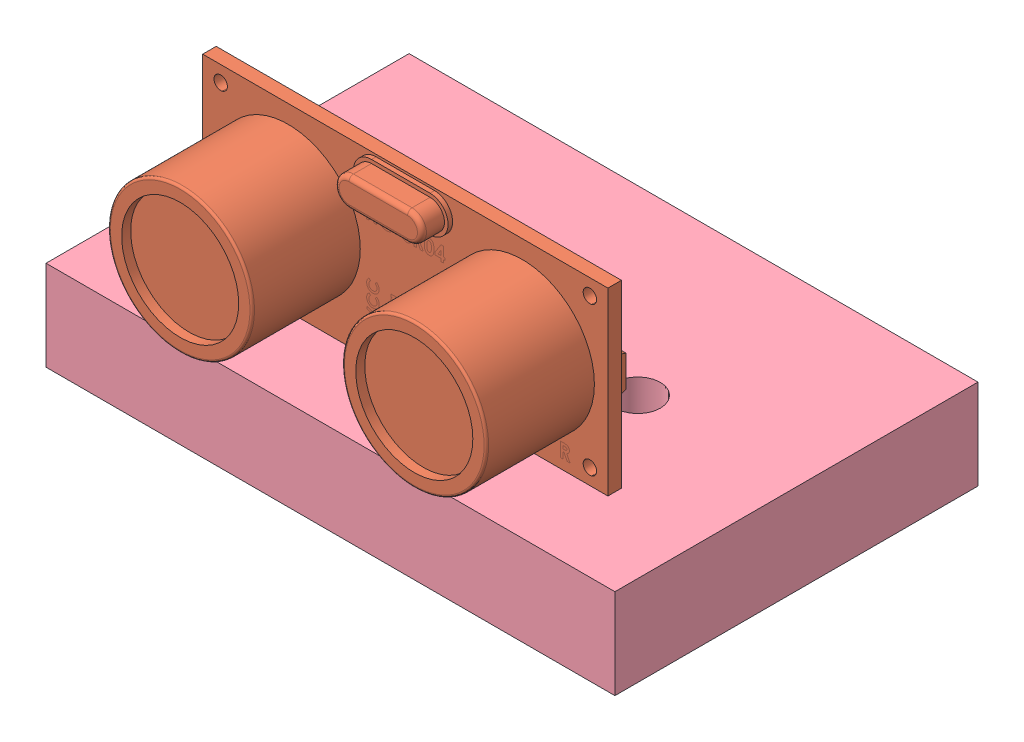
SolidWorks assembly Ultrasonic Jig, configuration Default. Lengths in mm.
Overall size (63.18 35.3 44.01).
8 component instances, 4 part files, 7 mates.
Components (placement in the parent):
- 01.01.03.00_Ultrasonic_with_mount-1: 01.01.03.00_Ultrasonic_with_mount [Default] at origin size (45 35.3 34.01)
  - 01.01.03.01_Ultrasonic_Vero-1: 01.01.03.01_Ultrasonic_Vero [Default] at origin size (43.18 10.5 20.32)
  - Ultrasonic-HCSR04-1: Ultrasonic-HCSR04 [Default] at (21.59 20.5 0.19) size (45 26.6 18)
  - hexagon nut style 1 (grades a and b) as-2: hexagon nut style 1 (grades a and b) as [AS 1112.1 S1 - M3-D-N] at (35.56 0 -10.16) x (0.865385 0 0.501108) z (0 1 0) size (5.5 6.35 2.4)
  - hexagon nut style 1 (grades a and b) as-3: hexagon nut style 1 (grades a and b) as [AS 1112.1 S1 - M3-D-N] at (35.56 -2.4 -10.16) x (0.865385 0 0.501108) z (0 1 0) size (5.5 6.35 2.4)
  - hexagon nut style 1 (grades a and b) as-6: hexagon nut style 1 (grades a and b) as [AS 1112.1 S1 - M3-D-N] at (7.62 0 -10.16) x (-0.001279 0 0.999999) z (0 1 0) size (5.5 6.35 2.4)
  - hexagon nut style 1 (grades a and b) as-7: hexagon nut style 1 (grades a and b) as [AS 1112.1 S1 - M3-D-N] at (7.62 -2.4 -10.16) x (-0.001279 0 0.999999) z (0 1 0) size (5.5 6.35 2.4)
- Ultrasonic Jig-1: Ultrasonic Jig [Default] x (1 0 0) z (0 1 0) size (63.18 40.32 10)
Mates (geometry in assembly coordinates):
- Coincident1: coincident aligned: plane of 01.01.03.00_Ultrasonic_with_mount-1 through (0 0 0) normal (0 0 1)
- Coincident2: coincident aligned: plane of 01.01.03.00_Ultrasonic_with_mount-1 through (0 0 0) normal (0 1 0)
- Coincident3: coincident aligned: plane of 01.01.03.00_Ultrasonic_with_mount-1 through (0 0 0) normal (1 0 0)
- InPlace1: in place: plane of Ultrasonic Jig-1 through (0 0 0) normal (0 1 0); moOrthogonalPlaneRef_w of Ultrasonic Jig-1 through (0 0 0) normal (0 0 -1); plane of Ultrasonic Jig-1 through (0 0 0) normal (1 0 0); unknown of Ultrasonic Jig-1
- Coincident4: coincident aligned: 
- Coincident5: coincident aligned: plane of Ultrasonic Jig-1 through (0 0 0) normal (0 0 -1)
- Coincident6: coincident anti-aligned: plane of Ultrasonic Jig-1 through (0 0 0) normal (1 0 0)
